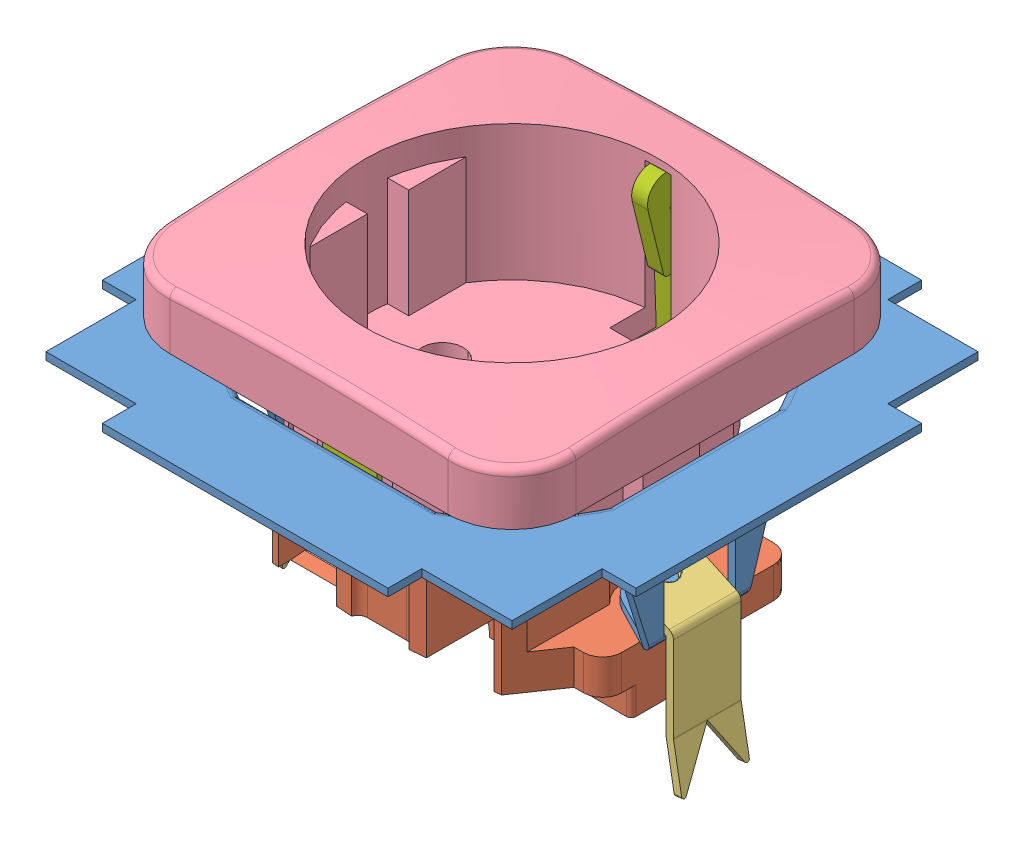
SolidWorks assembly Steckdose, configuration Standard. Lengths in mm.
Overall size (71 49.07 71).
8 component instances, 7 part files, 24 mates.
Components (placement in the parent):
- Montageplatte.02-1: Montageplatte.02 [Standard] at (-76.9981 11 50.9191) x (1 0 0) z (0 1 0) size (71 71 18.97)
- Halter-1: Halter [Standard] at (-76.9981 11 50.9191) x (1 0 0) z (0 1 0) size (45.97 31.9 15.37)
- Kralle.04-1: Kralle.04 [Standard] at (-74.3121 12.4168 50.9191) x (0.996195 -0.087156 0) z (0.087156 0.996195 0) size (8.78 9 23.36)
- Kralle.04-2: Kralle.04 [Standard] at (74.3121 12.4168 -50.9191) x (-0.996195 -0.087156 0) z (-0.087156 0.996195 0) size (8.78 9 23.36)
- Buchse-1: Buchse [Standard] at (-76.9981 11 50.9191) x (1 0 0) z (0 1 0) size (64.03 64.03 27)
- Stromklemme_1.02-1: Stromklemme_1.02 [Standard] at (-76.9981 11 50.7921) x (1 0 0) z (0 1 0) size (8.38 19.82 12.51)
- Stromklemme_2.02-1: Stromklemme_2.02 [Standard] at (-76.9981 11 50.7921) x (1 0 0) z (0 1 0) size (8.38 19.82 12.51)
- Erdleiter-1: Erdleiter [Standard] at (-76.9981 11 50.9191) x (1 0 0) z (0 1 0) size (7.24 44.01 27.12)
Mates (geometry in assembly coordinates):
- Abstand1: distance = 0.25 mm anti-aligned: plane of Kralle.04-1 through (-24.2693 -8.7605 4.5) normal (0 0 1); plane of Montageplatte.02-1 through (-42.6 -16.9704 4.75) normal (0 0 -1)
- Abstand2: distance = 0.25 mm anti-aligned: plane of Montageplatte.02-1 through (-42.6 -9.4704 -4.75) normal (0 0 1); plane of Kralle.04-2 through (24.2693 -8.7605 -4.5) normal (0 0 -1)
- Konzentrisch1: concentric aligned: cylinder of Montageplatte.02-1 through (19.9062 -17.9704 0) axis (0 1 0) radius 2; cylinder of Halter-1 through (19.9062 -27.8383 0) axis (0 1 0) radius 1.5
- Konzentrisch2: concentric aligned: cylinder of Montageplatte.02-1 through (-19.9062 -17.9704 0) axis (0 1 0) radius 2; cylinder of Halter-1 through (-19.9062 -27.8383 0) axis (0 1 0) radius 1.5
- Deckungsgleich9: coincident anti-aligned: plane of Montageplatte.02-1 through (19.1482 -17.9704 -1.7145) normal (0 -1 0); plane of Halter-1 through (-19.812 -17.9704 0.129) normal (0 1 0)
- Abstand3: distance = 2 mm anti-aligned: plane of Halter-1 through (-22.987 -26.3016 1.5875) normal (-1 0 0); plane of Kralle.04-1 through (-24.987 -28.4819 0) normal (1 0 0)
- Deckungsgleich13: coincident: line of Montageplatte.02-1 through (-25 -16.9704 4.75) axis (0 0 -1); plane of Kralle.04-1 through (-16.8482 -13.1691 0) normal (0.422618 -0.906308 0)
- Abstand4: distance = 2 mm anti-aligned: plane of Halter-1 through (22.987 -26.3016 1.5875) normal (1 0 0); plane of Kralle.04-2 through (24.987 -28.4819 0) normal (-1 0 0)
- Deckungsgleich15: coincident: plane of Kralle.04-2 through (16.8482 -13.1691 0) normal (-0.422618 -0.906308 0); line of Montageplatte.02-1 through (25 -16.9704 -4.75) axis (0 0 1)
- Deckungsgleich16: coincident anti-aligned: plane of Stromklemme_2.02-1 through (31.7915 -10.9346 -11.3157) normal (0 0 -1); plane of Halter-1 through (35.8778 -19.3928 -11.3157) normal (0 0 1)
- Deckungsgleich17: coincident anti-aligned: plane of Stromklemme_2.02-1 through (-14.351 -20.6234 13.0937) normal (-1 0 0); plane of Halter-1 through (-14.351 -20.6234 13.2207) normal (1 0 0)
- Deckungsgleich18: coincident anti-aligned: plane of Stromklemme_1.02-1 through (52.1115 -10.9346 -11.3157) normal (0 0 -1); plane of Halter-1 through (35.8778 -19.3928 -11.3157) normal (0 0 1)
- Deckungsgleich19: coincident anti-aligned: plane of Stromklemme_1.02-1 through (5.969 -20.6234 13.0937) normal (-1 0 0); plane of Halter-1 through (5.969 -19.3928 1.5875) normal (1 0 0)
- Deckungsgleich20: coincident anti-aligned: plane of Stromklemme_1.02-1 through (14.224 -19.3928 -17.6809) normal (0 -1 0); plane of Halter-1 through (14.224 -19.3928 -17.5539) normal (0 1 0)
- Deckungsgleich21: coincident anti-aligned: plane of Stromklemme_2.02-1 through (-6.096 -19.3928 -17.6809) normal (0 -1 0); plane of Halter-1 through (-6.096 -19.3928 -17.5539) normal (0 1 0)
- Deckungsgleich22: coincident anti-aligned: plane of Erdleiter-1 through (-3.6195 -14.6176 0) normal (0 -1 0); plane of Halter-1 through (3.81 -14.6176 -14.3637) normal (0 1 0)
- Konzentrisch5: concentric anti-aligned: cylinder of Erdleiter-1 through (0 -14.6176 0) axis (0 1 0) radius 1.5875; cylinder of Halter-1 through (0 -10.9346 0) axis (0 -1 0) radius 1.5875
- Parallel5: parallel anti-aligned: plane of Halter-1 through (-3.81 -14.6176 -14.3637) normal (1 0 0); plane of Erdleiter-1 through (-3.6195 -12.0776 17.3365) normal (-1 0 0)
- Konzentrisch6: concentric aligned: cylinder of Buchse-1 through (0 16.2 0) axis (0 -1 0) radius 1.5; cylinder of Halter-1 through (0 -10.9346 0) axis (0 -1 0) radius 1.5875
- Parallel6: parallel anti-aligned: plane of Buchse-1 through (-3.5 -6.5 -4.5) normal (-1 0 0); plane of Halter-1 through (-3.81 -14.6176 -14.3637) normal (1 0 0)
- Deckungsgleich26: coincident anti-aligned: plane of Montageplatte.02-1 through (-35.5 0 34) normal (0 -1 0); plane of assembly through (0 0 0) normal (0 1 0)
- Konzentrisch7: concentric: cylinder of ? through (0 -10.9346 0) axis (0 -1 0) radius 1.5875
- Parallel7: parallel anti-aligned: plane of Montageplatte.02-1 through (-35.5 1 -19) normal (-1 0 0); plane of assembly through (0 0 0) normal (1 0 0)
- Deckungsgleich29: coincident anti-aligned: plane of Buchse-1 through (16.75 -13.5 0) normal (0 -1 0); plane of Erdleiter-1 through (0 -13.5 0) normal (0 1 0)
